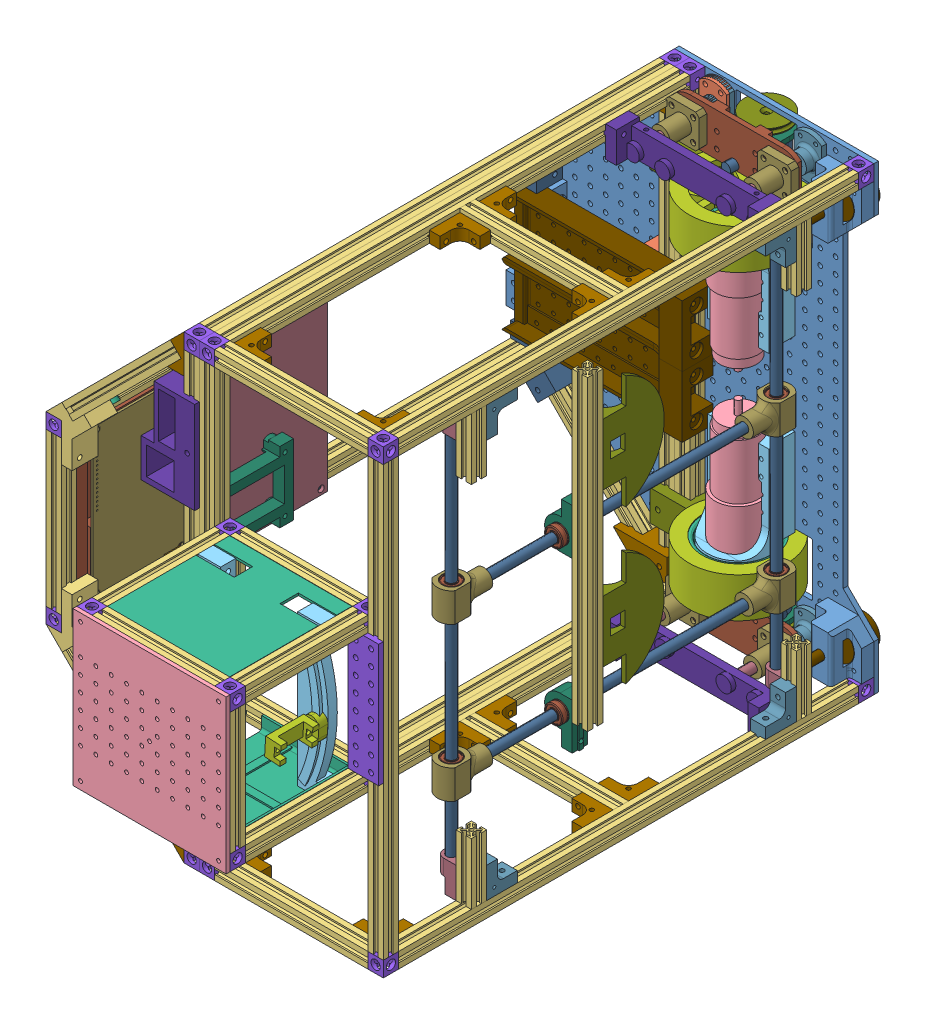
SolidWorks assembly BigRobot, configuration Default. Lengths in mm.
Overall size (302.19 309.6 437.94).
194 component instances, 52 part files, 53 mates.
Components (placement in the parent):
- Plate-BigRobot-Lower-3mm-1: Plate-BigRobot-Lower-3mm [Default] at (102.2592 151.0611 251.4915) size (220 300 3)
- KBH06-PP-1: KBH06-PP [Default] at (72.2592 286.0611 254.4915) size (18 28 19)
- Makerbeam50-1000mm-1: Makerbeam50-1000mm [280mm] at (57.2592 11.0611 259.4915) x (1 0 0) z (0 1 0) size (10 10 280)
- BigRobotMotorBlockLeftAssembly-2: BigRobotMotorBlockLeftAssembly [Default] at (185.4847 114.3207 220.2524) x (0 -1 0) z (-1 0 0) size (103.3 87.89 87.89)
  - 2642W_CR_with_30-1S-1: 2642W_CR_with_30-1S [Défaut] at (-28.6404 52.7391 83.2255) size (98.5 30 30)
  - BigRobotMotorSupport-1: BigRobotMotorSupport [Default] at (-9.7404 52.7391 83.2255) x (0 0 -1) z (1 0 0) size (40 38.5 65)
  - BigRobotWheelHub-1: BigRobotWheelHub [Default] at (49.2596 52.7391 83.2255) x (0 0.797707 -0.603046) z (0 -0.603046 -0.797707) size (47 17.4 47)
  - Wheel-Traction-63x26mm-1: Wheel-Traction-63x26mm [Défaut] at (48.6596 52.7391 83.2255) x (0 -0.85563 0.517588) z (1 0 0) size (64 64 26)
- BigRobotMakerBeamCentralFrame-1: BigRobotMakerBeamCentralFrame [Default] at (54.5242 178.5841 688.927) x (1 0 0) z (0 0 -1) size (120 300 320)
  - BigRobotMakerBeamLeftFrame-1: BigRobotMakerBeamLeftFrame [Default] at (96.7704 -16.2623 -10.9933) size (120 10 320)
    - BigRobotMakerBeamFrame-1: BigRobotMakerBeamFrame [Default] at (45.5821 193.9563 421.287) size (10 10 320)
      - MakerBeam-cube-1: MakerBeam-cube [Default] at (-29.6175 -5.1709 14.1418) size (10 10 10)
      - Makerbeam50-1000mm-1: Makerbeam50-1000mm [300mm] at (-29.6175 -5.1709 -285.8582) size (10 10 300)
      - MakerBeam-cube-2: MakerBeam-cube [Default] at (-34.6175 -5.1709 -290.8582) x (0 0 -1) z (1 0 0) size (10 10 10)
    - BigRobotMakerBeamFrame-2: BigRobotMakerBeamFrame [Default] at (-99.2064 218.4029 421.287) x (0 1 0) z (0 0 1) size (10 10 320)
      - MakerBeam-cube-1: MakerBeam-cube [Default] at (-29.6175 -5.1709 14.1418) size (10 10 10)
      - Makerbeam50-1000mm-1: Makerbeam50-1000mm [300mm] at (-29.6175 -5.1709 -285.8582) size (10 10 300)
      - MakerBeam-cube-2: MakerBeam-cube [Default] at (-34.6175 -5.1709 -290.8582) x (0 0 -1) z (1 0 0) size (10 10 10)
    - Makerbeam50-1000mm-1: Makerbeam50-1000mm [100mm] at (10.9645 188.7853 130.4289) x (0 1 0) z (-1 0 0) size (10 10 100)
    - Bracket_L_Big_20x20_ForWindow-1: Bracket_L_Big_20x20_ForWindow [Default] at (-89.0355 183.7853 135.4289) x (0 0 1) z (0 1 0) size (21 21 7.5)
    - Bracket_L_Big_20x20_ForWindow-2: Bracket_L_Big_20x20_ForWindow [Default] at (10.9645 183.7853 135.4289) x (-1 0 0) z (0 1 0) size (21 21 7.5)
    - Makerbeam50-1000mm-2: Makerbeam50-1000mm [100mm] at (-89.0355 188.7853 290.4289) x (0 -1 0) z (1 0 0) size (10 10 100)
    - Bracket_L_Big_20x20_ForWindow-3: Bracket_L_Big_20x20_ForWindow [Default] at (-89.0355 183.7853 295.4289) x (0 0 1) z (0 1 0) size (21 21 7.5)
    - Bracket_L_Big_20x20_ForWindow-4: Bracket_L_Big_20x20_ForWindow [Default] at (10.9645 183.7853 295.4289) x (-1 0 0) z (0 1 0) size (21 21 7.5)
    - Bracket_L_Big_20x20_ForWindow-5: Bracket_L_Big_20x20_ForWindow [Default] at (10.9645 191.2853 285.4289) x (-1 0 0) z (0 -1 0) size (21 21 7.5)
    - Bracket_L_Big_20x20_ForWindow-6: Bracket_L_Big_20x20_ForWindow [Default] at (-89.0355 191.2853 285.4289) x (0 0 -1) z (0 -1 0) size (21 21 7.5)
  - BigRobotMakerBeamLeftFrame-2: BigRobotMakerBeamLeftFrame [Default] at (18.6994 71.3084 -10.9933) x (-1 0 0) z (0 0 1) size (120 10 320)
    - BigRobotMakerBeamFrame-1: BigRobotMakerBeamFrame [Default] at (45.5821 193.9563 421.287) size (10 10 320)
      - MakerBeam-cube-1: MakerBeam-cube [Default] at (-29.6175 -5.1709 14.1418) size (10 10 10)
      - Makerbeam50-1000mm-1: Makerbeam50-1000mm [300mm] at (-29.6175 -5.1709 -285.8582) size (10 10 300)
      - MakerBeam-cube-2: MakerBeam-cube [Default] at (-34.6175 -5.1709 -290.8582) x (0 0 -1) z (1 0 0) size (10 10 10)
    - BigRobotMakerBeamFrame-2: BigRobotMakerBeamFrame [Default] at (-99.2064 218.4029 421.287) x (0 1 0) z (0 0 1) size (10 10 320)
      - MakerBeam-cube-1: MakerBeam-cube [Default] at (-29.6175 -5.1709 14.1418) size (10 10 10)
      - Makerbeam50-1000mm-1: Makerbeam50-1000mm [300mm] at (-29.6175 -5.1709 -285.8582) size (10 10 300)
      - MakerBeam-cube-2: MakerBeam-cube [Default] at (-34.6175 -5.1709 -290.8582) x (0 0 -1) z (1 0 0) size (10 10 10)
    - Makerbeam50-1000mm-1: Makerbeam50-1000mm [100mm] at (10.9645 188.7853 130.4289) x (0 1 0) z (-1 0 0) size (10 10 100)
    - Bracket_L_Big_20x20_ForWindow-1: Bracket_L_Big_20x20_ForWindow [Default] at (-89.0355 183.7853 135.4289) x (0 0 1) z (0 1 0) size (21 21 7.5)
    - Bracket_L_Big_20x20_ForWindow-2: Bracket_L_Big_20x20_ForWindow [Default] at (10.9645 183.7853 135.4289) x (-1 0 0) z (0 1 0) size (21 21 7.5)
    - Makerbeam50-1000mm-2: Makerbeam50-1000mm [100mm] at (-89.0355 188.7853 290.4289) x (0 -1 0) z (1 0 0) size (10 10 100)
    - Bracket_L_Big_20x20_ForWindow-3: Bracket_L_Big_20x20_ForWindow [Default] at (-89.0355 183.7853 295.4289) x (0 0 1) z (0 1 0) size (21 21 7.5)
    - Bracket_L_Big_20x20_ForWindow-4: Bracket_L_Big_20x20_ForWindow [Default] at (10.9645 183.7853 295.4289) x (-1 0 0) z (0 1 0) size (21 21 7.5)
    - Bracket_L_Big_20x20_ForWindow-5: Bracket_L_Big_20x20_ForWindow [Default] at (10.9645 191.2853 285.4289) x (-1 0 0) z (0 -1 0) size (21 21 7.5)
    - Bracket_L_Big_20x20_ForWindow-6: Bracket_L_Big_20x20_ForWindow [Default] at (-89.0355 191.2853 285.4289) x (0 0 -1) z (0 -1 0) size (21 21 7.5)
  - Makerbeam50-1000mm-1: Makerbeam50-1000mm [280mm] at (112.7349 -112.477 119.4356) x (1 0 0) z (0 1 0) size (10 10 280)
  - Makerbeam50-1000mm-2: Makerbeam50-1000mm [280mm] at (2.7349 167.523 119.4356) x (1 0 0) z (0 -1 0) size (10 10 280)
- BigRobotMotorBlockLeftAssembly-1: BigRobotMotorBlockLeftAssembly [Default] at (19.0337 187.8015 220.2524) x (0 1 0) z (1 0 0) size (103.3 87.89 87.89)
  - 2642W_CR_with_30-1S-1: 2642W_CR_with_30-1S [Défaut] at (-28.6404 52.7391 83.2255) size (98.5 30 30)
  - BigRobotMotorSupport-1: BigRobotMotorSupport [Default] at (-9.7404 52.7391 83.2255) x (0 0 -1) z (1 0 0) size (40 38.5 65)
  - BigRobotWheelHub-1: BigRobotWheelHub [Default] at (49.2596 52.7391 83.2255) x (0 0.797707 -0.603046) z (0 -0.603046 -0.797707) size (47 17.4 47)
  - Wheel-Traction-63x26mm-1: Wheel-Traction-63x26mm [Défaut] at (48.6596 52.7391 83.2255) x (0 -0.85563 0.517588) z (1 0 0) size (64 64 26)
- Coders-Scancon-2RMHF-1: Coders-Scancon-2RMHF [Défaut] at (102.2592 268.0611 254.4915) x (0 1 0) z (0.998001 0 0.063193) size (24.4 36.85 23.7)
- BigRobotEncoderLeftBlock-1: BigRobotEncoderLeftBlock [Default] at (82.3019 61.6374 337.5167) x (1 0 0) z (0 0 -1) size (99.6 39.6 73.98)
  - LMK06-Support-Link-1: LMK06-Support-Link [Default] at (19.9572 45.5763 64.5681) size (80.24 28 9.3)
  - LMK6UU-1: LMK6UU [Default] at (-10.0428 45.5763 44.0681) x (0 0 1) z (-0.707107 -0.707107 0) size (19 28 28)
  - LMK6UU-2: LMK6UU [Default] at (49.9572 45.5763 44.0681) x (0 0 1) z (-0.707107 -0.707107 0) size (19 28 28)
  - LinearShaft6x55mm-1: LinearShaft6x55mm [Default] at (-10.0428 45.5763 28.0252) x (0.980312 -0.197453 0) z (0 0 1) size (6 6 55)
  - LinearShaft6x55mm-2: LinearShaft6x55mm [Default] at (49.9572 45.5763 28.0252) size (6 6 55)
  - KH06-10PP-Axis-Support-1: KH06-10PP-Axis-Support [Default] at (-10.0428 45.5763 83.0252) x (1 0 0) z (0 0 -1) size (18 28 10)
  - KH06-10PP-Axis-Support-2: KH06-10PP-Axis-Support [Default] at (49.9572 45.5763 83.0252) x (-1 0 0) z (0 0 -1) size (18 28 10)
  - Support-BigRobot-Coders-Scancon-2RMHF-For-LinearBall-1: Support-BigRobot-Coders-Scancon-2RMHF-For-LinearBall [Default] at (19.9572 43.5763 95.0681) x (-1 0 0) z (0 0 -1) size (32 16 29)
  - Coders-Scancon-2RMHF-1: Coders-Scancon-2RMHF [Défaut] at (19.9572 26.2763 83.0681) x (0 1 0) z (-0.5 0 -0.866025) size (24.4 36.85 23.7)
  - Wheel-Free-With-Axis-27x5mm-1: Wheel-Free-With-Axis-27x5mm [Défaut] at (19.9572 53.6063 83.0681) x (-0.408581 0 0.912722) z (0.912722 0 0.408581) size (28.66 9.86 28.66)
- LinearJunctionTop2-1: LinearJunctionTop2 [Default] at (112.2592 1.0611 304.4915) size (102 20 15)
- BigRobotEncoderLeftBlock-2: BigRobotEncoderLeftBlock [Default] at (122.2164 240.4848 337.5167) x (-1 0 0) z (0 0 -1) size (99.6 39.6 73.98)
  - LMK06-Support-Link-1: LMK06-Support-Link [Default] at (19.9572 45.5763 64.5681) size (80.24 28 9.3)
  - LMK6UU-1: LMK6UU [Default] at (-10.0428 45.5763 44.0681) x (0 0 1) z (-0.707107 -0.707107 0) size (19 28 28)
  - LMK6UU-2: LMK6UU [Default] at (49.9572 45.5763 44.0681) x (0 0 1) z (-0.707107 -0.707107 0) size (19 28 28)
  - LinearShaft6x55mm-1: LinearShaft6x55mm [Default] at (-10.0428 45.5763 28.0252) x (0.980312 -0.197453 0) z (0 0 1) size (6 6 55)
  - LinearShaft6x55mm-2: LinearShaft6x55mm [Default] at (49.9572 45.5763 28.0252) size (6 6 55)
  - KH06-10PP-Axis-Support-1: KH06-10PP-Axis-Support [Default] at (-10.0428 45.5763 83.0252) x (1 0 0) z (0 0 -1) size (18 28 10)
  - KH06-10PP-Axis-Support-2: KH06-10PP-Axis-Support [Default] at (49.9572 45.5763 83.0252) x (-1 0 0) z (0 0 -1) size (18 28 10)
  - Support-BigRobot-Coders-Scancon-2RMHF-For-LinearBall-1: Support-BigRobot-Coders-Scancon-2RMHF-For-LinearBall [Default] at (19.9572 43.5763 95.0681) x (-1 0 0) z (0 0 -1) size (32 16 29)
  - Coders-Scancon-2RMHF-1: Coders-Scancon-2RMHF [Défaut] at (19.9572 26.2763 83.0681) x (0 1 0) z (-0.5 0 -0.866025) size (24.4 36.85 23.7)
  - Wheel-Free-With-Axis-27x5mm-1: Wheel-Free-With-Axis-27x5mm [Défaut] at (19.9572 53.6063 83.0681) x (-0.408581 0 0.912722) z (0.912722 0 0.408581) size (28.66 9.86 28.66)
- LinearJunctionTop2-2: LinearJunctionTop2 [Default] at (112.2592 301.0611 304.4915) x (-1 0 0) z (0 0 1) size (102 20 15)
- CareerBall12mm-1: CareerBall12mm [Default] at (157.2592 26.0611 290.4915) x (0 0 -1) z (1 0 0) size (48 20 20)
- CareerBall12mmSupport-1: CareerBall12mmSupport [Left] at (157.2592 276.0611 254.4915) size (30 30 20)
- CareerBall12mm-2: CareerBall12mm [Default] at (157.2592 276.0611 290.4915) x (0 0 -1) z (0.991257 -0.131947 0) size (48 20 20)
- CareerBall12mmSupport-2: CareerBall12mmSupport [Right] at (157.2592 -13.9389 254.4915) size (30 30 20)
- CareerBall24mmFixPiece-1: CareerBall24mmFixPiece [Défaut] at (-7.2408 136.0611 254.4915) x (0 1 0) z (0 0 1) size (30 30 10.16)
- CareerBall24mm-1: CareerBall24mm [Défaut] at (-22.7408 151.0611 262.4915) x (0.324019 0.946051 0) z (-0.946051 0.324019 0) size (31 21 31)
- SquareBeaconAssembly-1: SquareBeaconAssembly [Default] at (43.7066 120.2221 702.917) x (0 -1 0) z (1 0 0) size (100 102.5 120)
  - Makerbeam50-1000mm-1: Makerbeam50-1000mm [80mm] at (14.161 43.4255 28.5525) size (10 10 80)
  - MakerBeam-cube-1: MakerBeam-cube [Default] at (14.161 48.4255 113.5525) x (1 0 0) z (0 -1 0) size (10 10 10)
  - Makerbeam50-1000mm-2: Makerbeam50-1000mm [80mm] at (14.161 128.4255 113.5525) x (1 0 0) z (0 -1 0) size (10 10 80)
  - Makerbeam50-1000mm-3: Makerbeam50-1000mm [80mm] at (14.161 128.4255 23.5525) x (1 0 0) z (0 -1 0) size (10 10 80)
  - Makerbeam50-1000mm-4: Makerbeam50-1000mm [80mm] at (-70.839 43.4255 113.5525) x (0 0 -1) z (1 0 0) size (10 10 80)
  - Makerbeam50-1000mm-5: Makerbeam50-1000mm [80mm] at (-70.839 43.4255 23.5525) x (0 0 -1) z (1 0 0) size (10 10 80)
  - MakerBeam-cube-3: MakerBeam-cube [Default] at (9.161 43.4255 23.5525) x (0 -1 0) z (1 0 0) size (10 10 10)
  - MakerBeam-cube-4: MakerBeam-cube [Default] at (14.161 128.4255 23.5525) x (1 0 0) z (0 1 0) size (10 10 10)
  - Makerbeam50-1000mm-6: Makerbeam50-1000mm [80mm] at (14.161 133.4255 28.5525) size (10 10 80)
  - MakerBeam-cube-5: MakerBeam-cube [Default] at (14.161 133.4255 108.5525) size (10 10 10)
  - Makerbeam50-1000mm-7: Makerbeam50-1000mm [80mm] at (9.161 133.4255 113.5525) x (0 0 1) z (-1 0 0) size (10 10 80)
  - Makerbeam50-1000mm-8: Makerbeam50-1000mm [80mm] at (-70.839 133.4255 23.5525) x (0 0 -1) z (1 0 0) size (10 10 80)
  - Makerbeam50-1000mm-9: Makerbeam50-1000mm [80mm] at (-75.839 133.4255 28.5525) size (10 10 80)
  - Makerbeam50-1000mm-10: Makerbeam50-1000mm [80mm] at (-75.839 48.4255 113.5525) x (1 0 0) z (0 1 0) size (10 10 80)
  - MakerBeam-cube-6: MakerBeam-cube [Default] at (-75.839 133.4255 28.5525) x (-1 0 0) z (0 0 -1) size (10 10 10)
  - MakerBeam-cube-7: MakerBeam-cube [Default] at (-70.839 133.4255 113.5525) x (0 0 1) z (-1 0 0) size (10 10 10)
  - MakerBeam-cube-8: MakerBeam-cube [Default] at (-70.839 43.4255 113.5525) x (0 -1 0) z (-1 0 0) size (10 10 10)
  - Makerbeam50-1000mm-11: Makerbeam50-1000mm [80mm] at (-75.839 43.4255 28.5525) size (10 10 80)
  - MakerBeam-cube-9: MakerBeam-cube [Default] at (-70.839 43.4255 23.5525) x (0 0 -1) z (-1 0 0) size (10 10 10)
  - Makerbeam50-1000mm-12: Makerbeam50-1000mm [80mm] at (-75.839 128.4255 23.5525) x (1 0 0) z (0 -1 0) size (10 10 80)
  - SquareBeaconSupportTop-1: SquareBeaconSupportTop [Default] at (-30.839 35.9255 68.5525) x (1 0 0) z (0 1 0) size (100 100 12.5)
  - SquareBeaconVl530xSupport-1: SquareBeaconVl530xSupport [Default] at (-30.839 113.4255 8.5525) x (0 0 1) z (1 0 0) size (19.83 13 100)
  - SquareBeaconSide-1: SquareBeaconSide [Default] at (-80.839 88.3255 68.4525) x (0 0 -1) z (1 0 0) size (81.5 81.5 10)
  - SquareBeaconSide-2: SquareBeaconSide [Default] at (19.161 88.5255 68.4525) x (0 1 0) z (-1 0 0) size (81.5 81.5 10)
  - SquareBeaconVl530xSupport-2: SquareBeaconVl530xSupport [Default] at (-30.839 113.4255 128.5525) x (0 0 -1) z (-1 0 0) size (19.83 13 100)
  - TofSupport-1: TofSupport [Default] at (-33.9246 101.4255 -41.4401) x (0.998101 0 -0.061604) z (-0.061604 0 -0.998101) size (15.71 30.8 10.03)
  - Bracket_ParallelCorner20x80_slotType2-1: Bracket_ParallelCorner20x80_slotType2 [Default] at (9.161 125.4255 23.5525) x (0 0 1) z (-1 0 0) size (20 4 80)
  - Bracket_ParallelCorner20x80_slotType2-2: Bracket_ParallelCorner20x80_slotType2 [Default] at (-70.839 125.4255 113.5525) x (0 0 -1) z (1 0 0) size (20 4 80)
- BigRobotElectronicalBlock-1: BigRobotElectronicalBlock [Default] at (137.0717 -68.3276 418.5231) x (-1 0 0) z (0 1 0) size (136 326 300)
  - Makerbeam50-1000mm-1: Makerbeam50-1000mm [280mm] at (89.8125 150.9684 79.3886) size (10 10 280)
  - MakerBeam-cube-1: MakerBeam-cube [Default] at (89.8125 150.9684 359.3886) x (0 1 0) z (0 0 1) size (10 10 10)
  - Makerbeam50-1000mm-2: Makerbeam50-1000mm [300mm] at (89.8125 145.9684 364.3886) x (0 0 1) z (0 -1 0) size (10 10 300)
  - MakerBeam-cube-2: MakerBeam-cube [Default] at (94.8125 -159.0316 364.3886) x (0 -1 0) z (-1 0 0) size (10 10 10)
  - Makerbeam50-1000mm-3: Makerbeam50-1000mm [280mm] at (89.8125 -159.0316 79.3886) size (10 10 280)
  - ElectronicalMakerBeamBottomFix45-1: ElectronicalMakerBeamBottomFix45 [Right] at (94.8125 -164.0316 69.3886) x (0 0 -1) z (0 1 0) size (25 35 15)
  - Makerbeam50-1000mm-5: Makerbeam50-1000mm [300mm] at (89.8125 145.9684 74.3886) x (0 0 -1) z (0 -1 0) size (10 10 300)
  - MakerBeam-cube-3: MakerBeam-cube [Default] at (94.8125 -159.0316 74.3886) x (0 0 -1) z (-1 0 0) size (10 10 10)
  - Makerbeam50-1000mm-6: Makerbeam50-1000mm [100mm] at (100.2145 -159.0316 81.8617) x (0.707107 0 -0.707107) z (0.707107 0 0.707107) size (10 10 100)
  - MakerBeam-cube-4: MakerBeam-cube [Default] at (89.8125 150.9684 79.3886) x (-1 0 0) z (0 0 -1) size (10 10 10)
  - ElectronicalMakerBeamBottomFix135-1: ElectronicalMakerBeamBottomFix135 [Right] at (94.8125 -164.0316 69.3886) x (0 0 -1) z (0 1 0) size (37.68 29.7 17)
  - Makerbeam50-1000mm-7: Makerbeam50-1000mm [100mm] at (179.8125 -159.0316 169.3886) size (10 10 100)
  - Makerbeam50-1000mm-8: Makerbeam50-1000mm [300mm] at (179.8125 -154.0316 164.3886) x (0 0 1) z (0 1 0) size (10 10 300)
  - MakerBeam-cube-5: MakerBeam-cube [Default] at (174.8125 -159.0316 164.3886) x (0 -1 0) z (1 0 0) size (10 10 10)
  - ElectronicalMakerBeamBottomFix45-2: ElectronicalMakerBeamBottomFix45 [Left] at (94.8125 155.9684 129.3886) x (0 0 1) z (0 -1 0) size (25 35 15)
  - Makerbeam50-1000mm-9: Makerbeam50-1000mm [100mm] at (100.2145 150.9684 81.8617) x (0.707107 0 -0.707107) z (0.707107 0 0.707107) size (10 10 100)
  - MakerBeam-cube-6: MakerBeam-cube [Default] at (179.8125 145.9684 164.3886) x (1 0 0) z (0 1 0) size (10 10 10)
  - Makerbeam50-1000mm-10: Makerbeam50-1000mm [100mm] at (179.8125 150.9684 169.3886) size (10 10 100)
  - MakerBeam-cube-7: MakerBeam-cube [Default] at (179.8125 150.9684 269.3886) size (10 10 10)
  - Makerbeam50-1000mm-11: Makerbeam50-1000mm [300mm] at (179.8125 145.9684 274.3886) x (1 0 0) z (0 -1 0) size (10 10 300)
  - MakerBeam-cube-8: MakerBeam-cube [Default] at (179.8125 -159.0316 269.3886) x (0 -1 0) z (0 0 1) size (10 10 10)
  - ElectronicalMakerBeamBottomFix135-3: ElectronicalMakerBeamBottomFix135 [Left] at (204.8125 -164.0316 369.3886) x (0 0 1) z (0 1 0) size (37.68 29.7 17)
  - Makerbeam50-1000mm-12: Makerbeam50-1000mm [100mm] at (170.6704 -159.0316 286.4597) x (0.707107 0 0.707107) z (-0.707107 0 0.707107) size (10 10 100)
  - Makerbeam50-1000mm-13: Makerbeam50-1000mm [100mm] at (170.9252 150.9684 286.2049) x (0.707107 0 0.707107) z (-0.707107 0 0.707107) size (10 10 100)
  - ElectronicalMakerBeamBottomFix45-3: ElectronicalMakerBeamBottomFix45 [Right] at (94.8125 155.9684 369.3886) x (0 0 1) z (0 -1 0) size (25 35 15)
  - ElectronicalMakerBeamBottomFix45-4: ElectronicalMakerBeamBottomFix45 [Left] at (94.8125 -164.0316 309.3886) x (0 0 -1) z (0 1 0) size (25 35 15)
  - 20X4LCD_SupportForBigRobot-1: 20X4LCD_SupportForBigRobot [Default] at (184.8125 78.9684 219.4386) x (-1 0 0) z (0 0 -1) size (12 69 103.9)
  - 20X4LCD JHD204A-1: 20X4LCD JHD204A [Default] at (172.8125 108.7157 219.3402) x (0 -0.000058 -1) z (0 -1 0.000058) size (98 9.76 60)
  - MotorBoard32_BigRobot_WithSupport-1: MotorBoard32_BigRobot_WithSupport [Default] at (277.5716 44.6572 296.8003) x (0 1 0) z (-1 0 0) size (90 121.5 15)
    - MotorBoard32-1: MotorBoard32 [Défaut] at (-10.6888 77.5617 108.2591) size (88 118.5 2)
    - MotorBoardElectronicalSupportForBigRobot-1: MotorBoardElectronicalSupportForBigRobot [Left] at (34.3112 27.4117 132.2591) x (0 1 0) z (-1 0 0) size (17.6 13 90)
    - MotorBoardElectronicalSupportForBigRobot-2: MotorBoardElectronicalSupportForBigRobot [Right] at (34.3112 127.7117 95.2591) x (0 -1 0) z (-1 0 0) size (17.6 13 90)
  - UsbBoardSupport-1: UsbBoardSupport [Défaut] at (87.3125 118.9684 257.8488) x (0 -1 0) z (1 0 0) size (55 46 10.5)
  - ElectronicalToMechanicalTopFixation-1: ElectronicalToMechanicalTopFixation [Default] at (81.0625 155.9684 159.3886) x (0 0 -1) z (0 1 0) size (20 27.5 16)
  - PowerSwitchSupport-1: PowerSwitchSupport [Default] at (102.3125 158.9684 304.8488) x (0 0 1) z (0 -1 0) size (60 35 28)
  - BatteriesBottomRackSmallRobot-1: BatteriesBottomRackSmallRobot [Default] at (121.0625 -154.0316 199.3886) x (0 0 -1) z (1 0 0) size (40 20 122.5)
  - BigRobot-ElectronicalBlock-BatteriesRackSmallSupport-1: BigRobot-ElectronicalBlock-BatteriesRackSmallSupport [Default] at (164.8125 -164.0316 179.3886) x (-1 0 0) z (0 0 1) size (31 10 20)
  - BigRobot-ElectronicalBlock-BatteriesRackBigSupport-1: BigRobot-ElectronicalBlock-BatteriesRackBigSupport [Default] at (104.8125 -164.0316 259.3886) x (1 0 0) z (0 0 -1) size (11 10 80)
  - ElectronicalMakerBeamTopFix135-1: ElectronicalMakerBeamTopFix135 [Left] at (204.8125 155.9684 69.3886) x (0 0 -1) z (0 -1 0) size (42.68 29.7 17)
  - ElectronicalMakerBeamTopFix135-2: ElectronicalMakerBeamTopFix135 [Right] at (94.8125 155.9684 369.3886) x (0 0 1) z (0 -1 0) size (42.68 29.7 17)
  - BatteriesBottomRackSmallRobot-2: BatteriesBottomRackSmallRobot [Default] at (121.0625 -154.0316 239.3886) x (0 0 -1) z (1 0 0) size (40 20 122.5)
  - BigRobot-ElectronicalBlock-BatteriesRackSmallSupport-2: BigRobot-ElectronicalBlock-BatteriesRackSmallSupport [Default] at (164.8125 -164.0316 239.3886) x (-1 0 0) z (0 0 1) size (31 10 20)
  - BigRobotWindowCorner90x90x45degSupport_PowerboardMiddle-1: BigRobotWindowCorner90x90x45degSupport_PowerboardMiddle [Default] at (135.8125 -35.4689 320.3886) x (0 0 -1) z (0 -1 0) size (92 92 22.5)
  - BigRobotWindowCorner90x90x45degCover-1: BigRobotWindowCorner90x90x45degCover [Default] at (139.8125 -29.2189 324.3886) x (0 0 -1) z (0 -1 0) size (90 90 10)
  - ElectronicalMainBoard-Support-1: ElectronicalMainBoard-Support [Défaut] at (143.4467 98.9684 320.7544) x (0.707107 0 -0.707107) z (-0.707107 0 -0.707107) size (104 95.5 12.5)
  - BigRobotWindowCorner90x90x45degSupport-1: BigRobotWindowCorner90x90x45degSupport [Default] at (136.3125 -113.1971 319.8886) x (0 0 -1) z (0 -1 0) size (93 93 10)
  - BigRobotWindowCorner90x90x45degCover-2: BigRobotWindowCorner90x90x45degCover [Default] at (140.3125 -113.1971 323.8886) x (0 0 -1) z (0 -1 0) size (90 90 10)
  - ElectronicalToMechanicalTopFixation-2: ElectronicalToMechanicalTopFixation [Default] at (81.0625 -154.0316 119.3886) x (0 0 -1) z (0 1 0) size (20 27.5 16)
  - ElectronicalToMechanicalTopFixation-3: ElectronicalToMechanicalTopFixation [Default] at (81.0625 -154.0316 319.3886) x (0 0 -1) z (0 1 0) size (20 27.5 16)
  - LCD_MiniVoltmeterSupport-1: LCD_MiniVoltmeterSupport [Default] at (97.8125 145.9684 200.8488) x (0 0 1) z (-1 0 0) size (40 10 5.5)
  - LCD_MiniVoltmeter-1: LCD_MiniVoltmeter [Default] at (99.3125 150.9684 225.8488) x (0 0 -1) z (1 0 0) size (30.25 10.15 8.4)
- BigRobotFork2019Assembly-1: BigRobotFork2019Assembly [Default] at (281.2666 360.8036 265.4498) x (-0.340743 0 0.940156) z (0 -1 0) size (221.39 101.13 282)
  - LinearShaft6mm_differentLengths-1: LinearShaft6mm_differentLengths [250mm] at (75.8296 107.6087 84.7425) size (6 6 250)
  - Lineare_bearing_LMUU_serie-1: Lineare_bearing_LMUU_serie [LM6UU] at (75.8296 107.6087 184.9075) x (1 0 0) z (0 -1 0) size (12 19 12)
  - LMUU6mm_Support_PerpendicularJunction_Shaft6mm-1: LMUU6mm_Support_PerpendicularJunction_Shaft6mm [Default] at (75.8296 107.6087 184.4075) x (-0.940156 0.340743 0) z (0 0 1) size (30 15.22 19)
  - ShaftMakerBeamSupport-1: ShaftMakerBeamSupport [Default] at (75.8296 107.6087 349.7425) x (0.340743 0.940156 0) z (0 0 -1) size (14 10 20)
  - Makerbeam50-1000mm-1: Makerbeam50-1000mm [40mm] at (71.4 95.3867 349.7425) x (0.340743 0.940156 0) z (0 0 -1) size (10 10 40)
  - Bracket_L_Big_20x20-1: Bracket_L_Big_20x20 [Default] at (77.8045 98.3838 349.7425) x (0 0 -1) z (-0.340743 -0.940156 0) size (21 21 10)
  - Makerbeam50-1000mm-2: Makerbeam50-1000mm [40mm] at (71.4 95.3867 109.7425) x (0.340743 0.940156 0) z (0 0 -1) size (10 10 40)
  - Bracket_L_Big_20x20-2: Bracket_L_Big_20x20 [Default] at (74.397 88.9822 69.7425) x (0 0 1) z (0.340743 0.940156 0) size (21 21 10)
  - ShaftMakerBeamSupport-2: ShaftMakerBeamSupport [Default] at (75.8296 107.6087 69.7425) x (0.340743 0.940156 0) z (0 0 1) size (14 10 20)
  - Lineare_bearing_LMUU_serie-2: Lineare_bearing_LMUU_serie [LM6UU] at (75.8296 107.6087 284.4075) x (1 0 0) z (0 -1 0) size (12 19 12)
  - LMUU6mm_Support_PerpendicularJunction_Shaft6mm-2: LMUU6mm_Support_PerpendicularJunction_Shaft6mm [Default] at (75.8296 107.6087 284.4075) x (-0.940156 0.340743 0) z (0 0 1) size (30 15.22 19)
  - LinearShaft6mm_differentLengths-2: LinearShaft6mm_differentLengths [200mm] at (269.5019 37.4156 284.4075) x (-0.29585 -0.816289 -0.49613) z (-0.940156 0.340743 0) size (6 6 200)
  - LinearShaft6mm_differentLengths-3: LinearShaft6mm_differentLengths [200mm] at (269.5019 37.4156 184.4075) x (0.053712 0.148199 0.987498) z (-0.940156 0.340743 0) size (6 6 200)
  - LMUU6mm_Support_PerpendicularJunction_Shaft6mm-3: LMUU6mm_Support_PerpendicularJunction_Shaft6mm [Default] at (275.1428 35.3711 284.4075) x (0.940156 -0.340743 0) z (0 0 1) size (30 15.22 19)
  - LMUU6mm_Support_PerpendicularJunction_Shaft6mm-4: LMUU6mm_Support_PerpendicularJunction_Shaft6mm [Default] at (275.1428 35.3711 184.4075) x (0.940156 -0.340743 0) z (0 0 1) size (30 15.22 19)
  - LinearShaft6mm_differentLengths-4: LinearShaft6mm_differentLengths [250mm] at (275.1428 35.3711 84.7425) size (6 6 250)
  - Lineare_bearing_LMUU_serie-3: Lineare_bearing_LMUU_serie [LM6UU] at (275.1428 35.3711 284.4075) x (1 0 0) z (0 -1 0) size (12 19 12)
  - Lineare_bearing_LMUU_serie-4: Lineare_bearing_LMUU_serie [LM6UU] at (275.1428 35.3711 184.4075) x (1 0 0) z (0 -1 0) size (12 19 12)
  - ShaftMakerBeamSupport-3: ShaftMakerBeamSupport [Default] at (275.1428 35.3711 349.7425) x (0.340743 0.940156 0) z (0 0 -1) size (14 10 20)
  - Makerbeam50-1000mm-3: Makerbeam50-1000mm [40mm] at (270.7131 23.1491 309.7425) x (0.340743 0.940156 0) z (0 0 1) size (10 10 40)
  - Bracket_L_Big_20x20-3: Bracket_L_Big_20x20 [Default] at (264.3086 20.152 349.7425) x (0 0 -1) z (0.340743 0.940156 0) size (21 21 10)
  - ShaftMakerBeamSupport-4: ShaftMakerBeamSupport [Default] at (275.1428 35.3711 69.7425) x (0.340743 0.940156 0) z (0 0 1) size (14 10 20)
  - Makerbeam50-1000mm-4: Makerbeam50-1000mm [40mm] at (270.7131 23.1491 69.7425) x (0.940156 -0.340743 0) z (0 0 1) size (10 10 40)
  - Bracket_L_Big_20x20-4: Bracket_L_Big_20x20 [Default] at (267.7161 29.5536 69.7425) x (0 0 1) z (-0.340743 -0.940156 0) size (21 21 10)
  - LM6UU_MakerBeamSupport-1: LM6UU_MakerBeamSupport [Default] at (199.1503 62.9133 184.4075) x (0 0 -1) z (0.940156 -0.340743 0) size (30 19 10)
  - Lineare_bearing_LMUU_serie-5: Lineare_bearing_LMUU_serie [LM6UU] at (203.8511 61.2096 184.4075) x (0.090429 0.249506 -0.964142) z (-0.328525 -0.906444 -0.265388) size (12 19 12)
  - Makerbeam50-1000mm-5: Makerbeam50-1000mm [200mm] at (199.4215 48.9875 87.2434) x (0.940156 -0.340743 0) z (0 0 1) size (10 10 200)
  - Lineare_bearing_LMUU_serie-6: Lineare_bearing_LMUU_serie [LM6UU] at (203.8511 61.2096 284.4075) x (0.337101 0.930107 -0.145823) z (0.049688 0.137097 0.989311) size (12 19 12)
  - LM6UU_MakerBeamSupport-2: LM6UU_MakerBeamSupport [Default] at (208.5519 59.5058 284.4075) x (0 0 1) z (-0.940156 0.340743 0) size (30 19 10)
  - ForkBottomBlock-1: ForkBottomBlock [Default] at (196.4244 55.392 235.7405) x (0 0 -1) z (-0.340743 -0.940156 0) size (74.16 41 10)
  - ForkBottomBlock-2: ForkBottomBlock [Default] at (196.4244 55.392 135.7405) x (0 0 -1) z (-0.340743 -0.940156 0) size (74.16 41 10)
Mates (geometry in assembly coordinates):
- Concentric1: concentric anti-aligned: cylinder of Plate-BigRobot-Lower-3mm-1 through (77.2592 296.0611 251.4915) axis (0 0 1) radius 1.5; cylinder of KBH06-PP-1 through (77.2592 296.0611 259.4915) axis (0 0 -1) radius 1.5
- Coincident1: coincident anti-aligned: plane of Plate-BigRobot-Lower-3mm-1 through (102.2592 151.0611 254.4915) normal (0 0 1); plane of KBH06-PP-1 through (72.2592 286.0611 254.4915) normal (0 0 -1)
- Concentric2: concentric anti-aligned: cylinder of Plate-BigRobot-Lower-3mm-1 through (67.2592 276.0611 251.4915) axis (0 0 1) radius 1.5; cylinder of KBH06-PP-1 through (67.2592 276.0611 259.4915) axis (0 0 -1) radius 1.5
- Coincident2: coincident anti-aligned: plane of Plate-BigRobot-Lower-3mm-1 through (102.2592 151.0611 254.4915) normal (0 0 1); plane of Makerbeam50-1000mm-1 through (52.2592 291.0611 254.4915) normal (0 0 -1)
- Distance1: distance = 10 mm aligned: plane of Makerbeam50-1000mm-1 through (57.2592 291.0611 259.4915) normal (0 1 0); plane of Plate-BigRobot-Lower-3mm-1 through (172.2592 301.0611 254.4915) normal (0 1 0)
- Distance2: distance = 30 mm aligned: plane of Plate-BigRobot-Lower-3mm-1 through (122.2592 298.0611 251.4915) normal (0 -1 0); plane of Coders-Scancon-2RMHF-1 through (101.5103 268.0611 266.3178) normal (0 -1 0)
- Coincident5: coincident: plane of Plate-BigRobot-Lower-3mm-1 through (102.2592 151.0611 251.4915) normal (1 0 0); line of Coders-Scancon-2RMHF-1 through (102.2592 328.2013 254.4915) axis (0 -1 0)
- Coincident6: coincident: plane of Plate-BigRobot-Lower-3mm-1 through (102.2592 151.0611 254.4915) normal (0 0 1); line of Coders-Scancon-2RMHF-1 through (102.2592 328.2013 254.4915) axis (0 -1 0)
- Coincident7: coincident anti-aligned: plane of Plate-BigRobot-Lower-3mm-1 through (102.2592 151.0611 254.4915) normal (0 0 1); plane of BigRobotMotorBlockLeftAssembly-1/BigRobotMotorSupport-1 through (109.8585 243.0611 254.4915) normal (0 0 -1)
- Concentric3: concentric anti-aligned: cylinder of Plate-BigRobot-Lower-3mm-1 through (117.2592 226.0611 251.4915) axis (0 0 1) radius 1.5; cylinder of BigRobotMotorBlockLeftAssembly-1/BigRobotMotorSupport-1 through (117.2592 226.0611 276.527) axis (0 0 -1) radius 1.25
- Concentric4: concentric anti-aligned: cylinder of Plate-BigRobot-Lower-3mm-1 through (87.2592 226.0611 251.4915) axis (0 0 1) radius 1.5; cylinder of BigRobotMotorBlockLeftAssembly-1/BigRobotMotorSupport-1 through (87.2592 226.0611 276.527) axis (0 0 -1) radius 1.25
- Coincident8: coincident anti-aligned: plane of Plate-BigRobot-Lower-3mm-1 through (102.2592 151.0611 254.4915) normal (0 0 1); plane of BigRobotMotorBlockLeftAssembly-2/BigRobotMotorSupport-1 through (94.6598 59.0611 254.4915) normal (0 0 -1)
- Concentric5: concentric anti-aligned: cylinder of Plate-BigRobot-Lower-3mm-1 through (117.2592 76.0611 251.4915) axis (0 0 1) radius 1.5; cylinder of BigRobotMotorBlockLeftAssembly-2/BigRobotMotorSupport-1 through (117.2592 76.0611 276.527) axis (0 0 -1) radius 1.25
- Concentric6: concentric anti-aligned: cylinder of Plate-BigRobot-Lower-3mm-1 through (87.2592 76.0611 251.4915) axis (0 0 1) radius 1.5; cylinder of BigRobotMotorBlockLeftAssembly-2/BigRobotMotorSupport-1 through (87.2592 76.0611 276.527) axis (0 0 -1) radius 1.25
- Coincident9: coincident anti-aligned: plane of Plate-BigRobot-Lower-3mm-1 through (102.2592 151.0611 254.4915) normal (0 0 1); plane of BigRobotMakerBeamCentralFrame-1/BigRobotMakerBeamLeftFrame-1/BigRobotMakerBeamFrame-2/MakerBeam-cube-1 through (57.2592 6.0611 254.4915) normal (0 0 -1)
- Concentric7: concentric anti-aligned: cylinder of Plate-BigRobot-Lower-3mm-1 through (57.2592 6.0611 251.4915) axis (0 0 1) radius 1.5; cylinder of BigRobotMakerBeamCentralFrame-1/BigRobotMakerBeamLeftFrame-1/BigRobotMakerBeamFrame-2/MakerBeam-cube-1 through (57.2592 6.0611 262.4915) axis (0 0 -1) radius 3
- Concentric8: concentric anti-aligned: cylinder of Plate-BigRobot-Lower-3mm-1 through (167.2592 6.0611 251.4915) axis (0 0 1) radius 1.5; cylinder of BigRobotMakerBeamCentralFrame-1/BigRobotMakerBeamLeftFrame-1/BigRobotMakerBeamFrame-1/MakerBeam-cube-1 through (167.2592 6.0611 254.4915) axis (0 0 -1) radius 1.25
- Concentric9: concentric aligned: cylinder of Makerbeam50-1000mm-1 through (57.2592 291.0611 259.4915) axis (0 -1 0) radius 1.25; cylinder of BigRobotMakerBeamCentralFrame-1/BigRobotMakerBeamLeftFrame-1/BigRobotMakerBeamFrame-2/MakerBeam-cube-1 through (57.2592 1.0611 259.4915) axis (0 -1 0) radius 1.25
- Coincident10: coincident anti-aligned: plane of Plate-BigRobot-Lower-3mm-1 through (102.2592 151.0611 254.4915) normal (0 0 1); plane of BigRobotEncoderLeftBlock-1/KH06-10PP-Axis-Support-1 through (72.2592 16.0611 254.4915) normal (0 0 -1)
- Concentric10: concentric anti-aligned: cylinder of Plate-BigRobot-Lower-3mm-1 through (67.2592 6.0611 251.4915) axis (0 0 1) radius 1.5; cylinder of BigRobotEncoderLeftBlock-1/KH06-10PP-Axis-Support-1 through (67.2592 6.0611 257.4915) axis (0 0 -1) radius 1.25
- Concentric11: concentric anti-aligned: cylinder of Plate-BigRobot-Lower-3mm-1 through (137.2592 6.0611 251.4915) axis (0 0 1) radius 1.5; cylinder of BigRobotEncoderLeftBlock-1/KH06-10PP-Axis-Support-2 through (137.2592 6.0611 257.4915) axis (0 0 -1) radius 1.25
- Coincident11: coincident anti-aligned: plane of Plate-BigRobot-Lower-3mm-1 through (102.2592 151.0611 254.4915) normal (0 0 1); plane of CareerBall12mmSupport-1 through (157.2592 276.0611 254.4915) normal (0 0 -1)
- Concentric12: concentric anti-aligned: cylinder of Plate-BigRobot-Lower-3mm-1 through (157.2592 276.0611 251.4915) axis (0 0 1) radius 10; cylinder of CareerBall12mmSupport-1 through (157.2592 276.0611 266.4915) axis (0 0 -1) radius 10.3
- Coincident12: coincident aligned: plane of Plate-BigRobot-Lower-3mm-1 through (172.2592 271.0611 254.4915) normal (1 0 0); plane of CareerBall12mmSupport-1 through (172.2592 271.0611 274.4915) normal (1 0 0)
- Concentric13: concentric anti-aligned: cylinder of CareerBall12mmSupport-1 through (157.2592 276.0611 266.4915) axis (0 0 -1) radius 10.3; cylinder of CareerBall12mm-2 through (157.2592 276.0611 292.8915) axis (0 0 1) radius 10
- Coincident13: coincident aligned: plane of CareerBall12mmSupport-1 through (157.2592 276.0611 262.4915) normal (0 0 1); plane of CareerBall12mm-2 through (157.655 279.0348 262.4915) normal (0 0 1)
- Concentric14: concentric anti-aligned: cylinder of Plate-BigRobot-Lower-3mm-1 through (157.2592 26.0611 251.4915) axis (0 0 1) radius 10; cylinder of CareerBall12mmSupport-2 through (157.2592 26.0611 266.4915) axis (0 0 -1) radius 10.3
- Coincident14: coincident anti-aligned: plane of Plate-BigRobot-Lower-3mm-1 through (102.2592 151.0611 254.4915) normal (0 0 1); plane of CareerBall12mmSupport-2 through (157.2592 26.0611 254.4915) normal (0 0 -1)
- Coincident15: coincident aligned: plane of Plate-BigRobot-Lower-3mm-1 through (172.2592 1.0611 254.4915) normal (1 0 0); plane of CareerBall12mmSupport-2 through (172.2592 31.0611 274.4915) normal (1 0 0)
- Concentric15: concentric aligned: cylinder of Plate-BigRobot-Lower-3mm-1 through (157.2592 26.0611 251.4915) axis (0 0 1) radius 10; cylinder of CareerBall12mm-1 through (157.2592 26.0611 292.8915) axis (0 0 1) radius 10
- Coincident16: coincident aligned: plane of CareerBall12mm-1 through (157.2592 29.0611 262.4915) normal (0 0 1); plane of CareerBall12mmSupport-2 through (157.2592 26.0611 262.4915) normal (0 0 1)
- Concentric16: concentric aligned: cylinder of Plate-BigRobot-Lower-3mm-1 through (-22.7408 151.0611 251.4915) axis (0 0 1) radius 12; cylinder of CareerBall24mm-1 through (-22.7408 151.0611 262.4915) axis (0 0 1) radius 12
- Coincident17: coincident anti-aligned: plane of Plate-BigRobot-Lower-3mm-1 through (102.2592 151.0611 251.4915) normal (0 0 -1); plane of CareerBall24mm-1 through (-18.8526 162.4137 251.4915) normal (0 0 1)
- Coincident18: coincident anti-aligned: plane of Plate-BigRobot-Lower-3mm-1 through (102.2592 151.0611 254.4915) normal (0 0 1); plane of CareerBall24mmFixPiece-1 through (-7.2408 136.0611 254.4915) normal (0 0 -1)
- Concentric17: concentric aligned: cylinder of CareerBall24mmFixPiece-1 through (-22.7408 151.0611 226.7561) axis (0 0 1) radius 12.25; cylinder of CareerBall24mm-1 through (-22.7408 151.0611 262.4915) axis (0 0 1) radius 12
- Parallel1: parallel aligned: plane of Plate-BigRobot-Lower-3mm-1 through (-47.7408 211.0611 254.4915) normal (-1 0 0); plane of CareerBall24mmFixPiece-1 through (-37.2408 136.0611 264.4915) normal (-1 0 0)
- Coincident20: coincident anti-aligned: plane of BigRobotMakerBeamCentralFrame-1/BigRobotMakerBeamLeftFrame-1/BigRobotMakerBeamFrame-2/Makerbeam50-1000mm-1 through (62.2592 7.5611 264.4915) normal (1 0 0); plane of LinearJunctionTop2-1 through (62.2592 7.5111 319.4915) normal (-1 0 0)
- Coincident21: coincident aligned: plane of BigRobotMakerBeamCentralFrame-1/BigRobotMakerBeamLeftFrame-1/BigRobotMakerBeamFrame-2/Makerbeam50-1000mm-1 through (52.2592 1.0611 264.4915) normal (0 -1 0); plane of LinearJunctionTop2-1 through (62.2592 1.0611 319.4915) normal (0 -1 0)
- Coincident22: coincident anti-aligned: plane of BigRobotEncoderLeftBlock-1/LinearShaft6x55mm-1 through (72.2592 16.0611 309.4915) normal (0 0 1); plane of LinearJunctionTop2-1 through (72.2592 16.0611 309.4915) normal (0 0 -1)
- Coincident23: coincident anti-aligned: plane of Plate-BigRobot-Lower-3mm-1 through (102.2592 151.0611 254.4915) normal (0 0 1); plane of BigRobotEncoderLeftBlock-2/KH06-10PP-Axis-Support-1 through (132.2592 286.0611 254.4915) normal (0 0 -1)
- Concentric18: concentric anti-aligned: cylinder of Plate-BigRobot-Lower-3mm-1 through (137.2592 296.0611 251.4915) axis (0 0 1) radius 1.5; cylinder of BigRobotEncoderLeftBlock-2/KH06-10PP-Axis-Support-1 through (137.2592 296.0611 257.4915) axis (0 0 -1) radius 1.25
- Concentric19: concentric anti-aligned: cylinder of Plate-BigRobot-Lower-3mm-1 through (67.2592 296.0611 251.4915) axis (0 0 1) radius 1.5; cylinder of BigRobotEncoderLeftBlock-2/KH06-10PP-Axis-Support-2 through (67.2592 296.0611 257.4915) axis (0 0 -1) radius 1.25
- Coincident24: coincident aligned: plane of BigRobotMakerBeamCentralFrame-1/BigRobotMakerBeamLeftFrame-2/BigRobotMakerBeamFrame-2/Makerbeam50-1000mm-1 through (165.7592 301.0611 264.4915) normal (0 1 0); plane of LinearJunctionTop2-2 through (162.2592 301.0611 319.4915) normal (0 1 0)
- Coincident26: coincident anti-aligned: plane of BigRobotMakerBeamCentralFrame-1/BigRobotMakerBeamLeftFrame-2/BigRobotMakerBeamFrame-2/Makerbeam50-1000mm-1 through (162.2592 294.5611 264.4915) normal (-1 0 0); plane of LinearJunctionTop2-2 through (162.2592 294.6111 319.4915) normal (1 0 0)
- Coincident27: coincident anti-aligned: plane of BigRobotEncoderLeftBlock-2/LinearShaft6x55mm-1 through (132.2592 286.0611 309.4915) normal (0 0 1); plane of LinearJunctionTop2-2 through (132.2592 286.0611 309.4915) normal (0 0 -1)
- Coincident28: coincident anti-aligned: plane of BigRobotMakerBeamCentralFrame-1/Makerbeam50-1000mm-1 through (162.2592 11.0611 574.4915) normal (0 0 1); plane of SquareBeaconAssembly-1/Bracket_ParallelCorner20x80_slotType2-2 through (172.2592 171.0611 574.4915) normal (0 0 -1)
- Coincident29: coincident anti-aligned: plane of BigRobotMakerBeamCentralFrame-1/Makerbeam50-1000mm-1 through (162.2592 11.0611 564.4915) normal (-1 0 0); plane of SquareBeaconAssembly-1/Makerbeam50-1000mm-7 through (162.2592 191.0611 564.4915) normal (1 0 0)
- Distance3: distance = 100 mm aligned: plane of BigRobotMakerBeamCentralFrame-1/BigRobotMakerBeamLeftFrame-2/Makerbeam50-1000mm-1 through (162.2592 301.0611 567.9915) normal (0 1 0); plane of SquareBeaconAssembly-1/Makerbeam50-1000mm-9 through (152.2592 201.0611 567.9915) normal (0 1 0)
- Coincident30: coincident anti-aligned: plane of Plate-BigRobot-Lower-3mm-1 through (102.2592 151.0611 254.4915) normal (0 0 1); plane of BigRobotElectronicalBlock-1/Makerbeam50-1000mm-3 through (45.7592 291.0611 254.4915) normal (0 0 -1)
- Coincident31: coincident aligned: plane of Plate-BigRobot-Lower-3mm-1 through (42.2592 1.0611 254.4915) normal (0 -1 0); plane of BigRobotElectronicalBlock-1/MakerBeam-cube-3 through (52.2592 1.0611 264.4915) normal (0 -1 0)
- Coincident32: coincident anti-aligned: plane of BigRobotMakerBeamCentralFrame-1/BigRobotMakerBeamLeftFrame-1/BigRobotMakerBeamFrame-2/MakerBeam-cube-1 through (52.2592 1.0611 254.4915) normal (-1 0 0); plane of BigRobotElectronicalBlock-1/MakerBeam-cube-3 through (52.2592 6.0611 259.4915) normal (1 0 0)
- Coincident33: coincident aligned: plane of BigRobotMakerBeamCentralFrame-1/BigRobotMakerBeamLeftFrame-1/BigRobotMakerBeamFrame-1/Makerbeam50-1000mm-1 through (172.2592 7.5611 264.4915) normal (1 0 0); plane of BigRobotFork2019Assembly-1/Makerbeam50-1000mm-1 through (172.2592 51.0611 301.5745) normal (1 0 0)
- Coincident34: coincident anti-aligned: plane of BigRobotMakerBeamCentralFrame-1/BigRobotMakerBeamLeftFrame-1/BigRobotMakerBeamFrame-1/Makerbeam50-1000mm-1 through (168.7592 11.0611 264.4915) normal (0 1 0); plane of BigRobotFork2019Assembly-1/Bracket_L_Big_20x20-1 through (172.2592 11.0611 325.0745) normal (0 -1 0)
